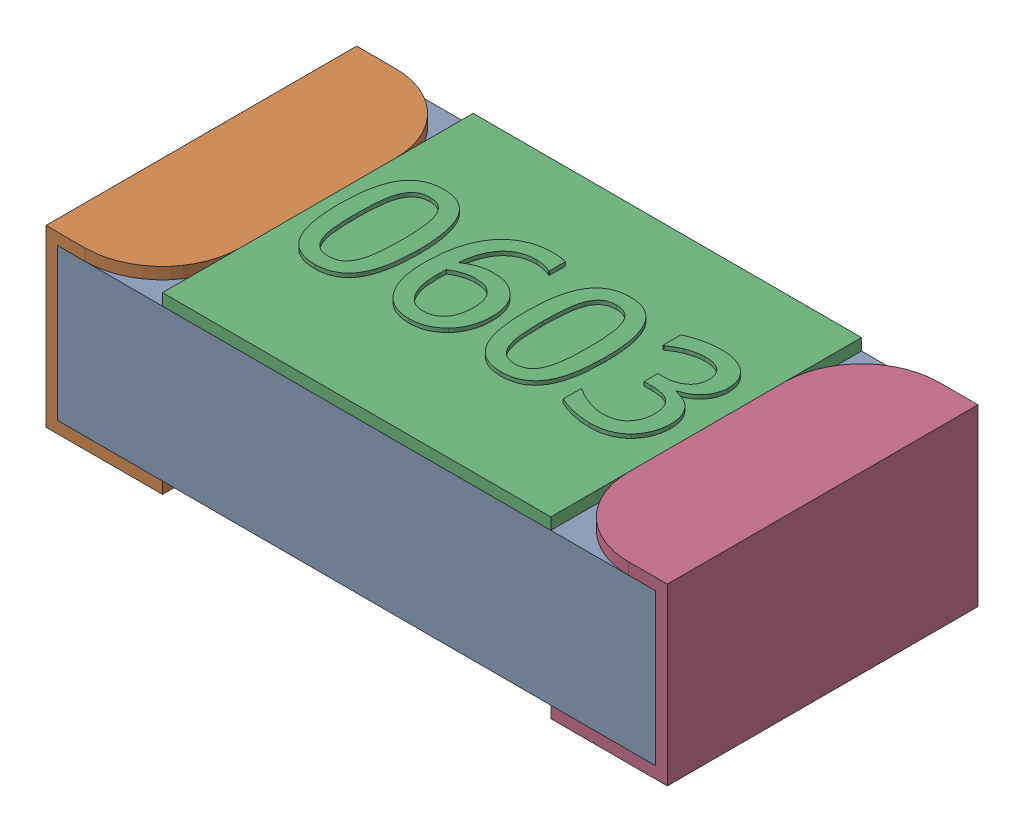
SolidWorks assembly 0603_RES, configuration 默认. Lengths in mm.
Overall size (1.6 0.46 0.8).
4 component instances, 3 part files, 0 mates.
Components (placement in the parent):
- Capsule-1: Capsule [默认] at origin size (1.54 0.39 0.8)
- Encapsulation-1: Encapsulation [默认] at (-0.8 -0.03 0.4) size (0.3 0.45 0.8)
- TopCover-1: TopCover [默认] at (0 0.39 0) size (1 0.04 0.8)
- Encapsulation-2: Encapsulation [默认] at (0.8 -0.03 -0.4) x (-1 0 0) z (0 0 -1) size (0.3 0.45 0.8)
